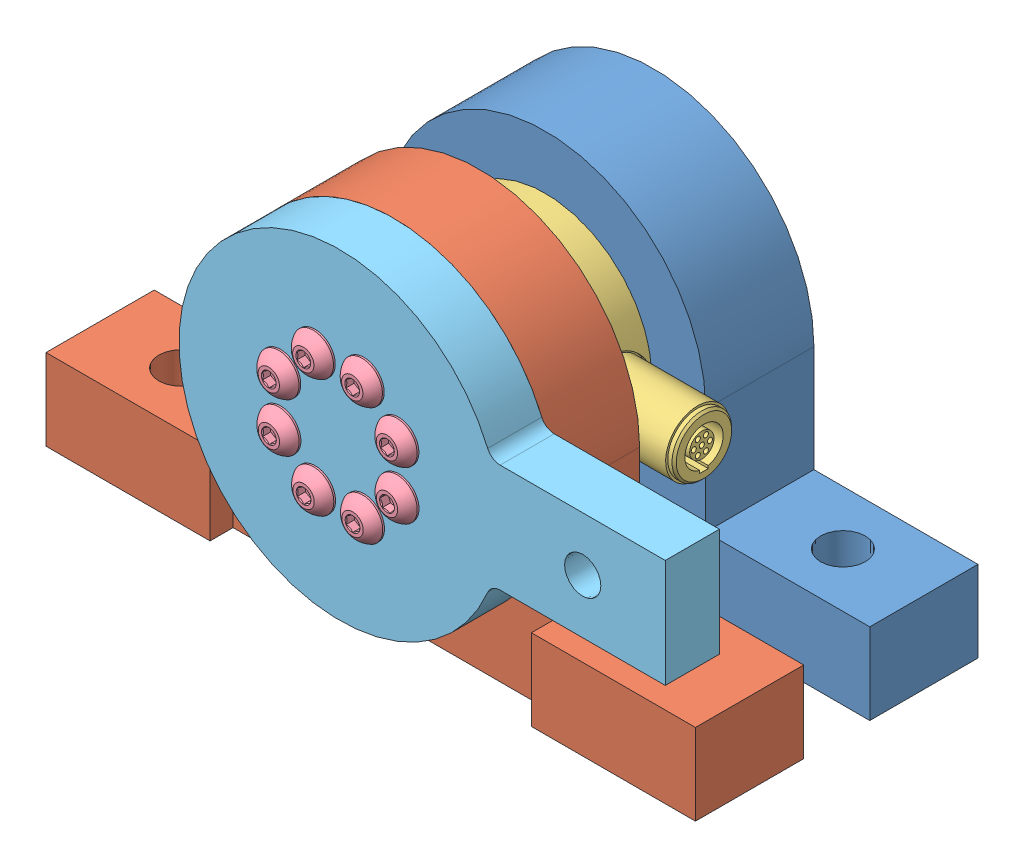
SolidWorks assembly torque sensor mount assembly, configuration Default. Lengths in mm.
Overall size (152.62 81.75 79.45).
20 component instances, 5 part files, 44 mates.
Components (placement in the parent):
- torque sensor back mount-1: torque sensor back mount [Default] at (57.4777 88.5559 104.0765) size (152.4 81.75 25.4)
- torque sensor front mount-1: torque sensor front mount [Default] at (57.4777 88.5559 144.9765) size (152.4 81.75 25.4)
- torque sensor-1: torque sensor [Default] at (57.4777 88.5559 167.9765) x (0 0 -1) z (-0.380356 -0.92484 0) size (61 69.28 50)
- m5 screw-1: m5 screw [91306A666] at (43.634 82.7807 101.3265) x (-0.923728 -0.383049 0) z (0 0 -1) size (9.5 9.5 15.22)
- m5 screw-2: m5 screw [91306A666] at (71.3214 94.331 101.3265) x (-0.923728 -0.383049 0) z (0 0 -1) size (9.5 9.5 15.22)
- m5 screw-3: m5 screw [91306A666] at (71.3503 82.8505 101.3265) x (-0.923728 -0.383049 0) z (0 0 -1) size (9.5 9.5 15.22)
- m5 screw-4: m5 screw [91306A666] at (51.7724 74.6833 101.3265) x (-0.923728 -0.383049 0) z (0 0 -1) size (9.5 9.5 15.22)
- m5 screw-5: m5 screw [91306A666] at (43.6051 94.2612 101.3265) x (0.923728 0.383049 0) z (0 0 -1) size (9.5 9.5 15.22)
- m5 screw-6: m5 screw [91306A666] at (63.2528 74.7122 101.3265) x (-0.923728 -0.383049 0) z (0 0 -1) size (9.5 9.5 15.22)
- m5 screw-7: m5 screw [91306A666] at (63.1831 102.4285 101.3265) x (-0.923728 -0.383049 0) z (0 0 -1) size (9.5 9.5 15.22)
- m5 screw-8: m5 screw [91306A666] at (51.7026 102.3996 101.3265) x (-0.923728 -0.383049 0) z (0 0 -1) size (9.5 9.5 15.22)
- torque sensor lever arm-1: torque sensor lever arm [Default] at (57.4777 88.5559 164.9765) size (114.12 75.4 12.7)
- m5 screw-9: m5 screw [91306A666] at (51.7026 102.3996 180.4265) size (9.5 9.5 15.22)
- m5 screw-10: m5 screw [91306A666] at (71.3503 82.8505 180.4265) x (0.941757 0.336296 0) z (0 0 1) size (9.5 9.5 15.22)
- m5 screw-11: m5 screw [91306A666] at (63.1831 102.4285 180.4265) size (9.5 9.5 15.22)
- m5 screw-12: m5 screw [91306A666] at (43.6051 94.2612 180.4265) size (9.5 9.5 15.22)
- m5 screw-13: m5 screw [91306A666] at (43.634 82.7807 180.4265) size (9.5 9.5 15.22)
- m5 screw-14: m5 screw [91306A666] at (71.3214 94.331 180.4265) size (9.5 9.5 15.22)
- m5 screw-15: m5 screw [91306A666] at (51.7724 74.6833 180.4265) size (9.5 9.5 15.22)
- m5 screw-16: m5 screw [91306A666] at (63.2528 74.7122 180.4265) size (9.5 9.5 15.22)
Mates (geometry in assembly coordinates):
- Coincident1: coincident aligned: plane of torque sensor back mount-1 through (57.4777 63.5559 129.4765) normal (0 1 0); plane of torque sensor front mount-1 through (57.4777 63.5559 164.9765) normal (0 1 0)
- Concentric1: concentric aligned: cylinder of torque sensor front mount-1 through (57.4777 88.5559 164.9765) axis (0 0 -1) radius 25; line of assembly
- Concentric2: concentric anti-aligned: cylinder of torque sensor-1 through (57.4777 88.5559 157.6671) axis (0 0 1) radius 4; line of assembly
- Coincident5: coincident anti-aligned: plane of torque sensor back mount-1 through (57.4777 88.5559 107.4765) normal (0 0 1); plane of torque sensor-1 through (57.4223 110.5558 107.4765) normal (0 0 -1)
- Tangent1: tangent anti-aligned: plane of torque sensor front mount-1 through (57.4777 88.5559 144.9765) normal (0 0 -1); cylinder of torque sensor-1 through (76.2777 88.7761 137.4765) axis (-1 0 0) radius 7.5
- Parallel1: parallel anti-aligned: plane of torque sensor back mount-1 through (133.6777 88.5559 129.4765) normal (1 0 0); plane of torque sensor-1 through (102.7777 88.7761 134.2265) normal (-1 0 0)
- Coincident7: coincident anti-aligned: plane of torque sensor back mount-1 through (57.4777 88.5559 104.0765) normal (0 0 -1); plane of m5 screw-7 through (65.0025 98.0407 104.0765) normal (0 0 1)
- Concentric3: concentric aligned: cylinder of torque sensor back mount-1 through (63.1831 102.4285 114.0765) axis (0 0 -1) radius 2.5; cylinder of m5 screw-7 through (63.1831 102.4285 101.3265) axis (0 0 -1) radius 4.75
- Coincident8: coincident anti-aligned: plane of torque sensor back mount-1 through (57.4777 88.5559 104.0765) normal (0 0 -1); plane of m5 screw-8 through (53.5221 98.0118 104.0765) normal (0 0 1)
- Concentric4: concentric aligned: cylinder of torque sensor back mount-1 through (51.7026 102.3996 114.0765) axis (0 0 -1) radius 2.5; circle of m5 screw-8
- Coincident9: coincident anti-aligned: plane of torque sensor back mount-1 through (57.4777 88.5559 104.0765) normal (0 0 -1); plane of m5 screw-2 through (73.1409 89.9433 104.0765) normal (0 0 1)
- Concentric5: concentric aligned: cylinder of torque sensor back mount-1 through (71.3214 94.331 114.0765) axis (0 0 -1) radius 2.5; cylinder of m5 screw-2 through (71.3214 94.331 101.3265) axis (0 0 -1) radius 4.75
- Coincident10: coincident anti-aligned: plane of torque sensor back mount-1 through (57.4777 88.5559 104.0765) normal (0 0 -1); plane of m5 screw-3 through (73.1698 78.4628 104.0765) normal (0 0 1)
- Concentric6: concentric aligned: cylinder of torque sensor back mount-1 through (71.3503 82.8505 114.0765) axis (0 0 -1) radius 2.5; cylinder of m5 screw-3 through (71.3503 82.8505 101.3265) axis (0 0 -1) radius 4.75
- Coincident11: coincident anti-aligned: plane of torque sensor back mount-1 through (57.4777 88.5559 104.0765) normal (0 0 -1); plane of m5 screw-6 through (65.0723 70.3244 104.0765) normal (0 0 1)
- Concentric7: concentric aligned: cylinder of torque sensor back mount-1 through (63.2528 74.7122 114.0765) axis (0 0 -1) radius 2.5; cylinder of m5 screw-6 through (63.2528 74.7122 101.3265) axis (0 0 -1) radius 4.75
- Coincident12: coincident anti-aligned: plane of torque sensor back mount-1 through (57.4777 88.5559 104.0765) normal (0 0 -1); plane of m5 screw-4 through (53.5919 70.2955 104.0765) normal (0 0 1)
- Concentric8: concentric aligned: cylinder of torque sensor back mount-1 through (51.7724 74.6833 114.0765) axis (0 0 -1) radius 2.5; circle of m5 screw-4
- Coincident13: coincident anti-aligned: plane of torque sensor back mount-1 through (57.4777 88.5559 104.0765) normal (0 0 -1); plane of m5 screw-1 through (45.4535 78.393 104.0765) normal (0 0 1)
- Concentric9: concentric aligned: cylinder of torque sensor back mount-1 through (43.634 82.7807 114.0765) axis (0 0 -1) radius 2.5; cylinder of m5 screw-1 through (43.634 82.7807 101.3265) axis (0 0 -1) radius 4.75
- Coincident15: coincident anti-aligned: plane of torque sensor back mount-1 through (57.4777 88.5559 104.0765) normal (0 0 -1); plane of m5 screw-5 through (41.7856 98.6489 104.0765) normal (0 0 1)
- Concentric10: concentric aligned: cylinder of torque sensor back mount-1 through (43.6051 94.2612 114.0765) axis (0 0 -1) radius 2.5; cylinder of m5 screw-5 through (43.6051 94.2612 101.3265) axis (0 0 -1) radius 4.75
- InPlace1: in place: plane of torque sensor front mount-1 through (57.4777 88.5559 164.9765) normal (0 0 1); plane of ? through (0 0 164.9765) normal (0 0 1); moOrthogonalPlaneRef_w of torque sensor front mount-1 through (57.4777 88.5559 164.9765) normal (0 0 1); plane of ? through (0 0 164.9765) normal (0 1 0); plane of torque sensor front mount-1 through (57.4777 88.5559 164.9765) normal (0 0 1); plane of ? through (0 0 164.9765) normal (1 0 0); plane of torque sensor front mount-1 through (57.4777 88.5559 164.9765) normal (0 0 1); unknown of torque sensor lever arm-1
- Coincident16: coincident aligned: plane of torque sensor front mount-1; plane of torque sensor lever arm-1
- Coincident17: coincident aligned: moOrthogonalPlaneRef_w of torque sensor front mount-1 through (57.4777 88.5559 164.9765) normal (0 1 0); plane of torque sensor lever arm-1 through (57.4777 88.5559 164.9765) normal (0 1 0)
- Coincident18: coincident anti-aligned: moOrthogonalPlaneRef_w of torque sensor front mount-1 through (57.4777 88.5559 164.9765) normal (-1 0 0); plane of torque sensor lever arm-1 through (57.4777 88.5559 164.9765) normal (1 0 0)
- Concentric11: concentric aligned: cylinder of torque sensor front mount-1 through (57.4777 88.5559 164.9765) axis (0 0 -1) radius 37.7; cylinder of torque sensor lever arm-1 through (57.4777 88.5559 177.6765) axis (0 0 -1) radius 37.7
- Parallel2: parallel aligned: plane of torque sensor front mount-1 through (133.6777 88.5559 164.9765) normal (1 0 0); plane of torque sensor lever arm-1 through (133.895 88.5559 177.6765) normal (1 0 0)
- Concentric12: concentric anti-aligned: cylinder of torque sensor lever arm-1 through (63.2528 74.7122 177.6765) axis (0 0 -1) radius 2.5; cylinder of m5 screw-16 through (63.2528 74.7122 180.4265) axis (0 0 1) radius 4.75
- Concentric13: concentric anti-aligned: cylinder of torque sensor lever arm-1 through (51.7724 74.6833 177.6765) axis (0 0 -1) radius 2.5; cylinder of m5 screw-15 through (51.7724 74.6833 180.4265) axis (0 0 1) radius 4.75
- Concentric14: concentric anti-aligned: cylinder of torque sensor lever arm-1 through (43.634 82.7807 177.6765) axis (0 0 -1) radius 2.5; cylinder of m5 screw-13 through (43.634 82.7807 180.4265) axis (0 0 1) radius 4.75
- Concentric15: concentric anti-aligned: cylinder of torque sensor lever arm-1 through (43.6051 94.2612 177.6765) axis (0 0 -1) radius 2.5; circle of m5 screw-12
- Concentric16: concentric anti-aligned: cylinder of torque sensor lever arm-1 through (51.7026 102.3996 177.6765) axis (0 0 -1) radius 2.5; circle of m5 screw-9
- Concentric17: concentric anti-aligned: cylinder of torque sensor lever arm-1 through (63.1831 102.4285 177.6765) axis (0 0 -1) radius 2.5; cylinder of m5 screw-11 through (63.1831 102.4285 180.4265) axis (0 0 1) radius 4.75
- Concentric18: concentric anti-aligned: cylinder of torque sensor lever arm-1 through (71.3214 94.331 177.6765) axis (0 0 -1) radius 2.5; circle of m5 screw-14
- Concentric19: concentric anti-aligned: cylinder of torque sensor lever arm-1 through (71.3503 82.8505 177.6765) axis (0 0 -1) radius 2.5; circle of m5 screw-10
- Coincident19: coincident anti-aligned: plane of torque sensor lever arm-1 through (57.4777 88.5559 177.6765) normal (0 0 1); plane of m5 screw-16 through (63.2528 69.9622 177.6765) normal (0 0 -1)
- Coincident20: coincident anti-aligned: plane of torque sensor lever arm-1 through (57.4777 88.5559 177.6765) normal (0 0 1); plane of m5 screw-15 through (51.7724 69.9333 177.6765) normal (0 0 -1)
- Coincident21: coincident anti-aligned: plane of torque sensor lever arm-1 through (57.4777 88.5559 177.6765) normal (0 0 1); plane of m5 screw-10 through (72.9477 78.3772 177.6765) normal (0 0 -1)
- Coincident22: coincident anti-aligned: plane of torque sensor lever arm-1 through (57.4777 88.5559 177.6765) normal (0 0 1); plane of m5 screw-14 through (71.3214 89.581 177.6765) normal (0 0 -1)
- Coincident23: coincident anti-aligned: plane of torque sensor lever arm-1 through (57.4777 88.5559 177.6765) normal (0 0 1); plane of m5 screw-12 through (43.6051 89.5112 177.6765) normal (0 0 -1)
- Coincident24: coincident anti-aligned: plane of torque sensor lever arm-1 through (57.4777 88.5559 177.6765) normal (0 0 1); plane of m5 screw-9 through (51.7026 97.6496 177.6765) normal (0 0 -1)
- Coincident25: coincident anti-aligned: plane of torque sensor lever arm-1 through (57.4777 88.5559 177.6765) normal (0 0 1); plane of m5 screw-13 through (43.634 78.0307 177.6765) normal (0 0 -1)
- Coincident26: coincident anti-aligned: plane of torque sensor lever arm-1 through (57.4777 88.5559 177.6765) normal (0 0 1); plane of m5 screw-11 through (63.1831 97.6785 177.6765) normal (0 0 -1)
